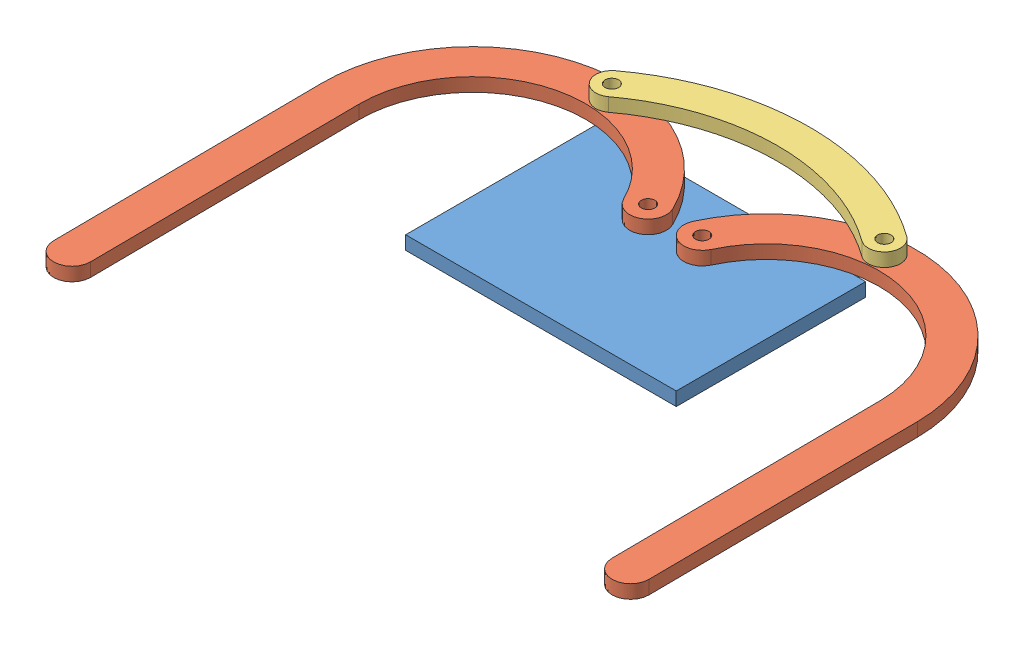
SolidWorks assembly Bumper Assembly, configuration Default. Lengths in mm.
Overall size (139.57 9.52 113.22).
4 component instances, 3 part files, 7 mates.
Components (placement in the parent):
- base-2: base [Default] at (-32.3945 61.9125 -19.2604) size (63.5 3.17 44.45)
- left bumper-4: left bumper [Default] at (-5.5317 65.0875 -3.868) x (0.999962 0 -0.008698) z (0.008698 0 0.999962) size (67.31 3.17 102.95)
- left bumper-5: left bumper [Default] at (4.2853 68.2625 -3.843) x (-0.999962 0 0.008675) z (0.008675 0 0.999962) size (67.31 3.17 102.95)
- connector-3: connector [Default] at (-3.1674 68.2625 -25.7615) x (0.999976 0 -0.006949) z (0.006949 0 0.999976) size (71.05 3.17 17.94)
Mates (geometry in assembly coordinates):
- Coincident19: coincident anti-aligned: plane of base-2 through (-32.3945 65.0875 25.1896) normal (0 1 0); plane of left bumper-4 through (-34.7376 65.0875 7.1065) normal (0 -1 0)
- Coincident21: coincident anti-aligned: plane of base-2 through (-32.3945 65.0875 25.1896) normal (0 1 0); plane of left bumper-5 through (33.6774 65.0875 6.6225) normal (0 -1 0)
- Coincident22: coincident anti-aligned: plane of left bumper-4 through (-34.7376 68.2625 7.1065) normal (0 1 0); plane of connector-3 through (15.2306 68.2625 -2.0364) normal (0 -1 0)
- Concentric1: concentric aligned: circle of base-2; circle of left bumper-4
- Concentric2: concentric anti-aligned: circle of base-2; circle of left bumper-5
- Concentric3: concentric aligned: circle of left bumper-4; circle of connector-3
- Concentric4: concentric anti-aligned: circle of left bumper-5; circle of connector-3
